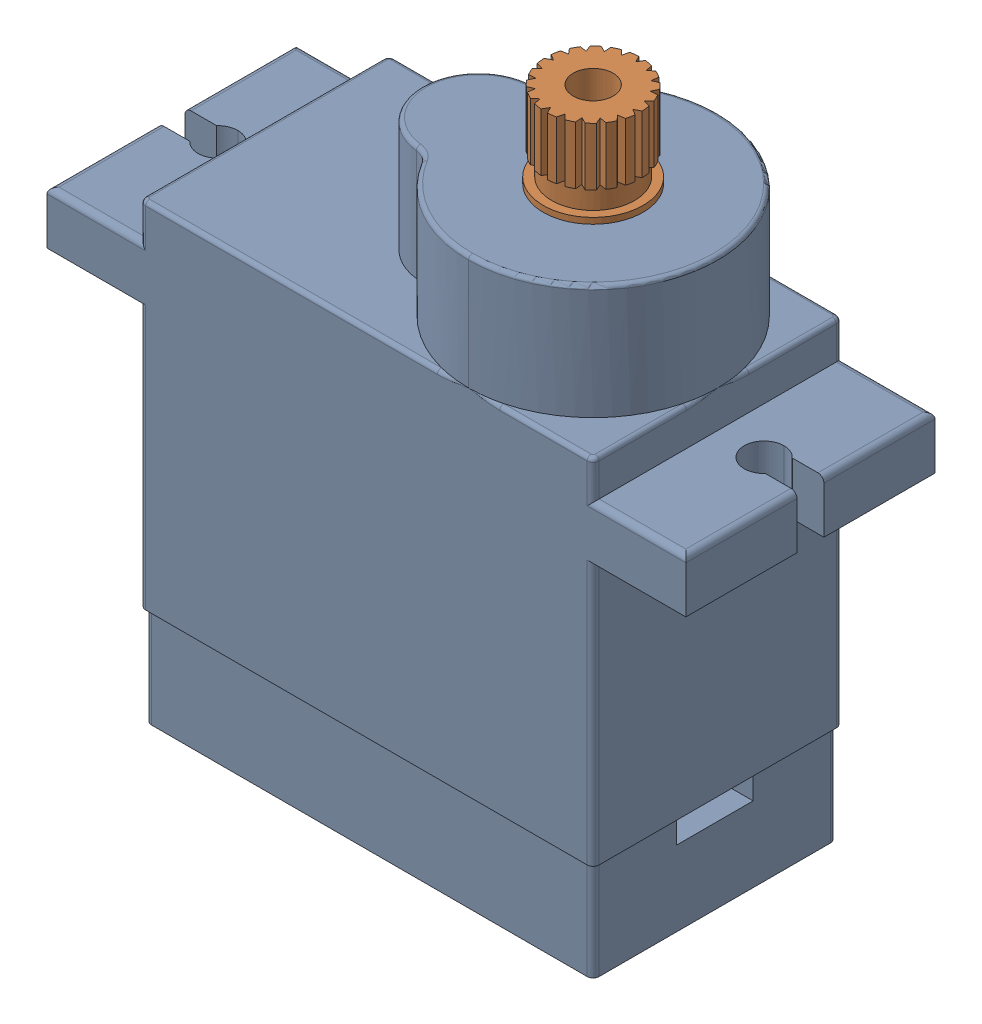
SolidWorks assembly MG90servo_assembly(2)^pet bot iteration one, configuration Default. Lengths in mm.
Overall size (32.05 32.8 12.51).
3 component instances, 3 part files, 0 mates.
Components (placement in the parent):
- MG90servo_body(2)^MG90servo_assembly(2)_pet bot iteration one-1: MG90servo_body(2)^MG90servo_assembly(2)_pet bot iteration one [Default] at origin size (32.05 28.5 12.51)
- MG90servo_shaft(2)^MG90servo_assembly(2)_pet bot iteration one-1: MG90servo_shaft(2)^MG90servo_assembly(2)_pet bot iteration one [Default] at (16.5 28.5 -6.25) x (0.786985 0 0.616972) z (-0.616972 0 0.786985) size (5 4.3 5)
- MG90servo_gear(2)^MG90servo_assembly(2)_pet bot iteration one-1: MG90servo_gear(2)^MG90servo_assembly(2)_pet bot iteration one [Default] at (16.5 34.45 -6.25) x (0.999514 0 0.031181) z (0.031181 0 -0.999514) (suppressed, hidden)
